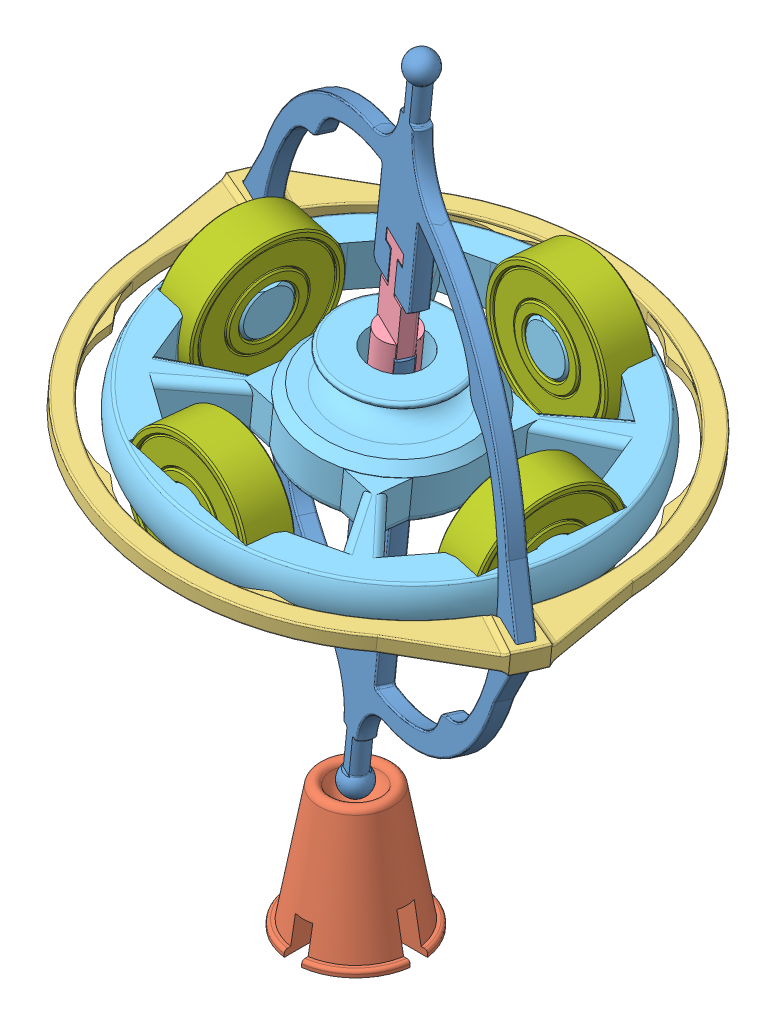
SolidWorks assembly TestAssem1, configuration Default. Lengths in mm.
Overall size (107.49 132.51 103).
11 component instances, 7 part files, 22 mates.
Components (placement in the parent):
- Test Main Frame-1: Test Main Frame [Default] at (55.4964 99.1663 145.5817) x (0.914058 -0.123728 0.386251) z (-0.123512 -0.992016 -0.025482) size (81.94 4.5 110.5)
- Spin Base-1: Spin Base [Default] at (49.012 47.0854 144.2439) size (19.87 20 19.87)
- Support Brace-1: Support Brace [Default] at (55.1147 99.2214 145.2848) x (0.914058 -0.123728 0.386251) z (-0.38632 0.024414 0.922042) size (85 3.53 76)
- Test key-1: Test key [Default] at (57.4246 113.9063 145.9993) x (-0.914058 0.123728 -0.386251) z (-0.123512 -0.992016 -0.025482) size (6 6 23.95)
- Test SPinny bOi-1: Test SPinny bOi [Default] at (55.6898 99.3958 145.5211) x (0.118629 0.010735 -0.992881) z (-0.985227 0.125656 -0.116356) size (64.5 14.5 64.5)
- TestAdapter-1: TestAdapter [Default] at (56.1221 102.8678 145.6103) x (-0.38632 0.024414 0.922042) z (0.914058 -0.123728 0.386251) size (8.3 8 7.59)
- Bearing-1: Bearing [Default] at (30.5665 102.6 142.5541) x (0.137683 0.985227 -0.101841) z (-0.101841 0.116356 0.987973) size (21.95 7 21.95)
- Bearing-2: Bearing [Default] at (55.4038 98.4223 145.5626) x (0.992342 -0.123512 -0.00158) z (-0.00158 -0.025482 0.999674) size (21.95 7 21.95)
- Bearing-3: Bearing [Default] at (80.8131 96.1915 148.4882) x (0.137683 0.985227 -0.101841) z (-0.101841 0.116356 0.987973) size (21.95 7 21.95)
- Bearing-4: Bearing [Default] at (52.6648 99.122 170.8396) x (0.986077 -0.118629 0.116534) z (0.116534 0.992881 0.024658) size (21.95 7 21.95)
- Bearing-5: Bearing [Default] at (58.7149 99.6695 120.2027) x (0.986077 -0.118629 0.116534) z (0.116534 0.992881 0.024658) size (21.95 7 21.95)
Mates (geometry in assembly coordinates):
- Coincident1: coincident anti-aligned: plane of Test Main Frame-1 through (55.1061 99.9408 146.7534) normal (-0.123512 -0.992016 -0.025482); plane of Support Brace-1 through (55.2074 99.9654 145.3039) normal (0.123512 0.992016 0.025482)
- Coincident2: coincident anti-aligned: plane of Support Brace-1 through (54.9928 100.9788 146.1362) normal (0.38632 -0.024414 -0.922042); plane of Test Main Frame-1 through (55.2067 99.1846 146.2733) normal (-0.38632 0.024414 0.922042)
- Coincident3: coincident anti-aligned: plane of Test Main Frame-1 through (18.9353 104.0804 131.4888) normal (-0.914058 0.123728 -0.386251); plane of Support Brace-1 through (19.6209 105.2868 130.2529) normal (0.914058 -0.123728 0.386251)
- Concentric2: concentric: sphere of Test Main Frame-1; sphere of Spin Base-1
- Coincident4: coincident anti-aligned: plane of Test Main Frame-1 through (55.0135 99.1968 146.7343) normal (-0.38632 0.024414 0.922042); plane of TestAdapter-1 through (55.1278 99.1813 146.7826) normal (0.38632 -0.024414 -0.922042)
- Coincident5: coincident anti-aligned: plane of Test Main Frame-1 through (57.2797 98.9876 143.8934) normal (-0.914058 0.123728 -0.386251); plane of TestAdapter-1 through (56.4587 99.0395 145.8527) normal (0.914058 -0.123728 0.386251)
- Coincident6: coincident anti-aligned: plane of Test Main Frame-1 through (56.3656 99.1113 143.5072) normal (0.123512 0.992016 0.025482); plane of TestAdapter-1 through (55.6589 99.1478 145.5148) normal (-0.123512 -0.992016 -0.025482)
- Concentric3: concentric aligned: cylinder of Test SPinny bOi-1 through (55.2575 95.9237 145.432) axis (0.123512 0.992016 0.025482) radius 11.05; cylinder of TestAdapter-1 through (55.6589 99.1478 145.5148) axis (0.123512 0.992016 0.025482) radius 4.15
- Coincident7: coincident aligned: plane of Test SPinny bOi-1 through (56.1221 102.8678 145.6103) normal (0.123512 0.992016 0.025482); plane of TestAdapter-1 through (56.1221 102.8678 145.6103) normal (0.123512 0.992016 0.025482)
- Coincident8: coincident anti-aligned: plane of Test Main Frame-1 through (59.7525 126.3135 144.2059) normal (-0.123512 -0.992016 -0.025482); plane of Test key-1 through (59.4576 126.3256 145.1666) normal (0.123512 0.992016 0.025482)
- Coincident9: coincident aligned: plane of Test Main Frame-1 through (55.9793 99.1358 144.4292) normal (0.38632 -0.024414 -0.922042); plane of Test key-1 through (57.9075 113.8758 144.8468) normal (0.38632 -0.024414 -0.922042)
- Coincident10: coincident anti-aligned: plane of Test Main Frame-1 through (57.2797 98.9876 143.8934) normal (-0.914058 0.123728 -0.386251); plane of Test key-1 through (58.7301 113.7644 145.1944) normal (0.914058 -0.123728 0.386251)
- Concentric4: concentric aligned: cylinder of Test SPinny bOi-1 through (27.1182 103.0398 142.1468) axis (0.985227 -0.125656 0.116356) radius 4.075; cylinder of Bearing-1 through (27.1182 103.0398 142.1468) axis (0.985227 -0.125656 0.116356) radius 4.025
- Coincident11: coincident anti-aligned: plane of Test SPinny bOi-1 through (27.1182 103.0398 142.1468) normal (0.985227 -0.125656 0.116356); plane of Bearing-1 through (27.1182 103.0398 142.1468) normal (-0.985227 0.125656 -0.116356)
- Concentric5: concentric aligned: cylinder of Test SPinny bOi-1 through (59.1301 99.7071 116.7276) axis (-0.118629 -0.010735 0.992881) radius 4.075; cylinder of Bearing-5 through (59.1301 99.7071 116.7276) axis (-0.118629 -0.010735 0.992881) radius 4.025
- Coincident12: coincident anti-aligned: plane of Test SPinny bOi-1 through (59.1301 99.7071 116.7276) normal (-0.118629 -0.010735 0.992881); plane of Bearing-5 through (59.1301 99.7071 116.7276) normal (0.118629 0.010735 -0.992881)
- Concentric6: concentric anti-aligned: cylinder of Test SPinny bOi-1 through (52.2496 99.0845 174.3147) axis (0.118629 0.010735 -0.992881) radius 4.075; cylinder of Bearing-4 through (53.08 99.1596 167.3645) axis (-0.118629 -0.010735 0.992881) radius 4.025
- Coincident14: coincident anti-aligned: plane of Test SPinny bOi-1 through (52.2496 99.0845 174.3147) normal (0.118629 0.010735 -0.992881); plane of Bearing-4 through (52.2496 99.0845 174.3147) normal (-0.118629 -0.010735 0.992881)
- Concentric7: concentric anti-aligned: cylinder of Test SPinny bOi-1 through (84.2614 95.7517 148.8955) axis (-0.985227 0.125656 -0.116356) radius 4.075; cylinder of Bearing-3 through (77.3648 96.6313 148.081) axis (0.985227 -0.125656 0.116356) radius 4.025
- Coincident15: coincident anti-aligned: plane of Test SPinny bOi-1 through (84.2614 95.7517 148.8955) normal (-0.985227 0.125656 -0.116356); plane of Bearing-3 through (84.2614 95.7517 148.8955) normal (0.985227 -0.125656 0.116356)
- Concentric8: concentric aligned: cylinder of Test Main Frame-1 through (48.6723 44.3574 144.1738) axis (-0.123512 -0.992016 -0.025482) radius 4.15; cylinder of Bearing-2 through (55.8361 101.8943 145.6518) axis (-0.123512 -0.992016 -0.025482) radius 4.025
- Coincident16: coincident anti-aligned: plane of Test SPinny bOi-1 through (55.9986 101.8758 145.5848) normal (-0.123512 -0.992016 -0.025482); plane of Bearing-2 through (55.8361 101.8943 145.6518) normal (0.123512 0.992016 0.025482)
